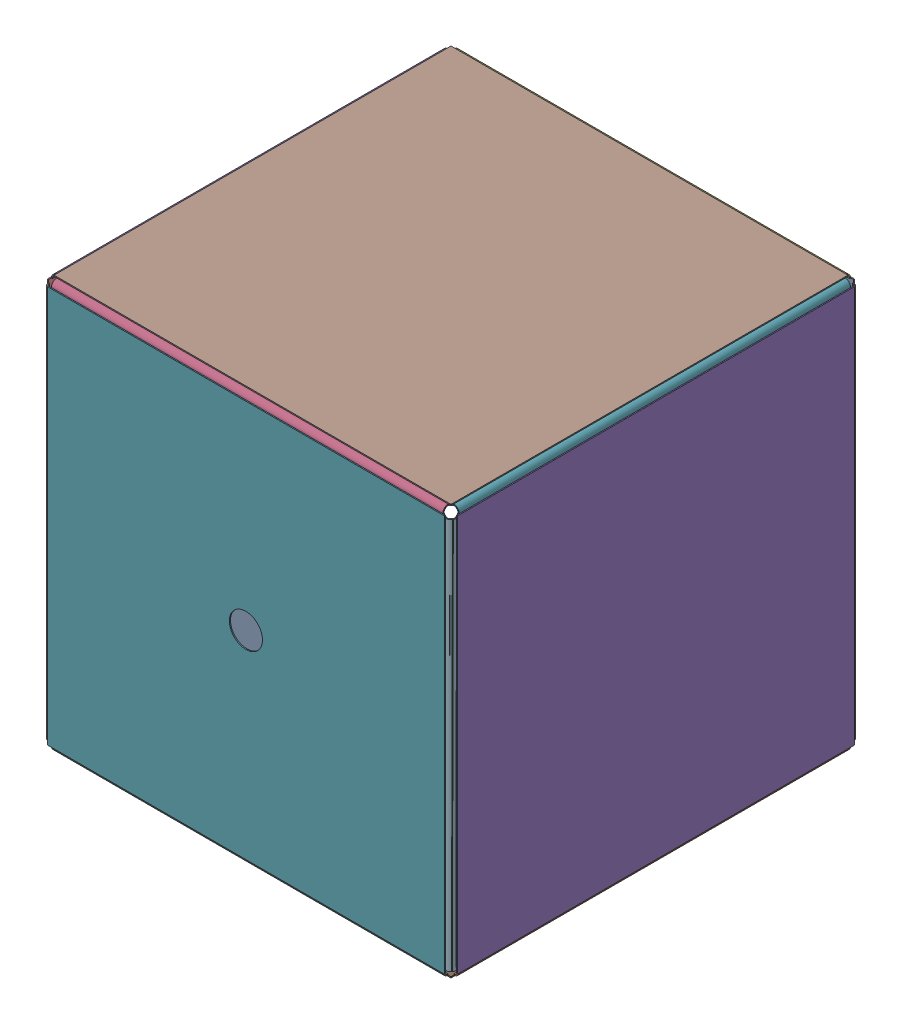
SolidWorks assembly full_mini_MSR, configuration Default. Lengths in mm.
Overall size (744 744 744).
46 component instances, 6 part files, 0 mates.
Components (placement in the parent):
- inner_layer-2: inner_layer [Default] at origin size (653 653 653)
  - inner_flat_front-5: inner_flat_front [Default] at (0 0 326.5) x (-1 0 0) z (0 0 -1) size (626 626 3)
  - inner_bracket-44: inner_bracket [Default] at (323.5 0 268.5) x (1 0 0) z (0 0 -1) size (56.5 620 56.5)
  - inner_bracket-45: inner_bracket [Default] at (0 -323.5 268.5) x (0 -1 0) z (0 0 -1) size (56.5 620 56.5)
  - inner_flat-22: inner_flat [Default] at (325 0 0) x (0 0 -1) z (1 0 0) size (626 626 3)
  - inner_flat-23: inner_flat [Default] at (0 -325 0) x (1 0 0) z (0 -1 0) size (626 626 3)
  - inner_bracket-48: inner_bracket [Default] at (268.5 -323.5 0) x (0 -1 0) z (-1 0 0) size (56.5 620 56.5)
  - inner_flat-26: inner_flat [Default] at (0 0 -325) x (-1 0 0) z (0 0 -1) size (626 626 3)
  - inner_bracket-46: inner_bracket [Default] at (-323.5 0 268.5) x (-1 0 0) z (0 0 -1) size (56.5 620 56.5)
  - inner_bracket-47: inner_bracket [Default] at (0 323.5 268.5) x (0 1 0) z (0 0 -1) size (56.5 620 56.5)
  - inner_bracket-49: inner_bracket [Default] at (268.5 323.5 0) x (0 1 0) z (-1 0 0) size (56.5 620 56.5)
  - inner_flat-24: inner_flat [Default] at (-325 0 0) x (0 0 1) z (-1 0 0) size (626 626 3)
  - inner_bracket-50: inner_bracket [Default] at (-268.5 323.5 0) x (0 1 0) z (1 0 0) size (56.5 620 56.5)
  - inner_bracket-51: inner_bracket [Default] at (-268.5 -323.5 0) x (0 -1 0) z (1 0 0) size (56.5 620 56.5)
  - inner_bracket-52: inner_bracket [Default] at (0 -323.5 -268.5) x (0 -1 0) z (0 0 1) size (56.5 620 56.5)
  - inner_bracket-53: inner_bracket [Default] at (323.5 0 -268.5) size (56.5 620 56.5)
  - inner_bracket-54: inner_bracket [Default] at (0 323.5 -268.5) x (0 1 0) z (0 0 1) size (56.5 620 56.5)
  - inner_bracket-55: inner_bracket [Default] at (-323.5 0 -268.5) x (-1 0 0) z (0 0 1) size (56.5 620 56.5)
  - inner_flat-25: inner_flat [Default] at (0 325 0) x (-1 0 0) z (0 1 0) size (626 626 3)
- outer_layer-1: outer_layer [Default] at origin size (744 744 744)
  - outer_flat_front-2: outer_flat_front [Default] at (0 0 372) x (-1 0 0) z (0 0 -1) size (720 720 4)
  - outer_bracket-5: outer_bracket [Default] at (-368 0 313) x (-1 0 0) z (0 0 -1) size (57 710 57)
  - outer_bracket-6: outer_bracket [Default] at (0 -313 368) x (0 0 1) z (0 1 0) size (57 710 57)
  - outer_flat-1: outer_flat [Default] at (-370 0 0) x (0 0 1) z (-1 0 0) size (720 720 4)
  - outer_flat-2: outer_flat [Default] at (0 -370 0) x (1 0 0) z (0 -1 0) size (720 720 4)
  - outer_bracket-7: outer_bracket [Default] at (-313 -368 0) x (0 -1 0) z (1 0 0) size (57 710 57)
  - outer_flat-7: outer_flat [Default] at (0 0 -370) x (-1 0 0) z (0 0 -1) size (720 720 4)
  - outer_bracket-8: outer_bracket [Default] at (-368 0 -313) x (-1 0 0) z (0 0 1) size (57 710 57)
  - outer_bracket-9: outer_bracket [Default] at (368 0 313) x (1 0 0) z (0 0 -1) size (57 710 57)
  - outer_bracket-10: outer_bracket [Default] at (368 0 -313) size (57 710 57)
  - outer_flat-3: outer_flat [Default] at (370 0 0) x (0 0 -1) z (1 0 0) size (720 720 4)
  - outer_bracket-11: outer_bracket [Default] at (313 -368 0) x (0 -1 0) z (-1 0 0) size (57 710 57)
  - outer_bracket-12: outer_bracket [Default] at (-368 0 -313) x (-1 0 0) z (0 0 1) size (57 710 57)
  - outer_bracket-13: outer_bracket [Default] at (-368 0 313) x (-1 0 0) z (0 0 -1) size (57 710 57)
  - outer_flat-4: outer_flat [Default] at (-370 0 0) x (0 0 1) z (-1 0 0) size (720 720 4)
  - outer_bracket-14: outer_bracket [Default] at (-313 -368 0) x (0 -1 0) z (1 0 0) size (57 710 57)
  - outer_bracket-15: outer_bracket [Default] at (368 0 -313) size (57 710 57)
  - outer_bracket-16: outer_bracket [Default] at (368 0 313) x (1 0 0) z (0 0 -1) size (57 710 57)
  - outer_flat-5: outer_flat [Default] at (370 0 0) x (0 0 -1) z (1 0 0) size (720 720 4)
  - outer_bracket-17: outer_bracket [Default] at (313 -368 0) x (0 -1 0) z (-1 0 0) size (57 710 57)
  - outer_bracket-18: outer_bracket [Default] at (0 -313 -368) x (0 0 -1) z (0 1 0) size (57 710 57)
  - outer_bracket-19: outer_bracket [Default] at (0 313 368) x (0 0 1) z (0 -1 0) size (57 710 57)
  - outer_bracket-20: outer_bracket [Default] at (-313 368 0) x (0 1 0) z (1 0 0) size (57 710 57)
  - outer_bracket-21: outer_bracket [Default] at (0 313 -368) x (0 0 -1) z (0 -1 0) size (57 710 57)
  - outer_bracket-22: outer_bracket [Default] at (313 368 0) x (0 1 0) z (-1 0 0) size (57 710 57)
  - outer_flat-6: outer_flat [Default] at (0 370 0) x (-1 0 0) z (0 1 0) size (720 720 4)
